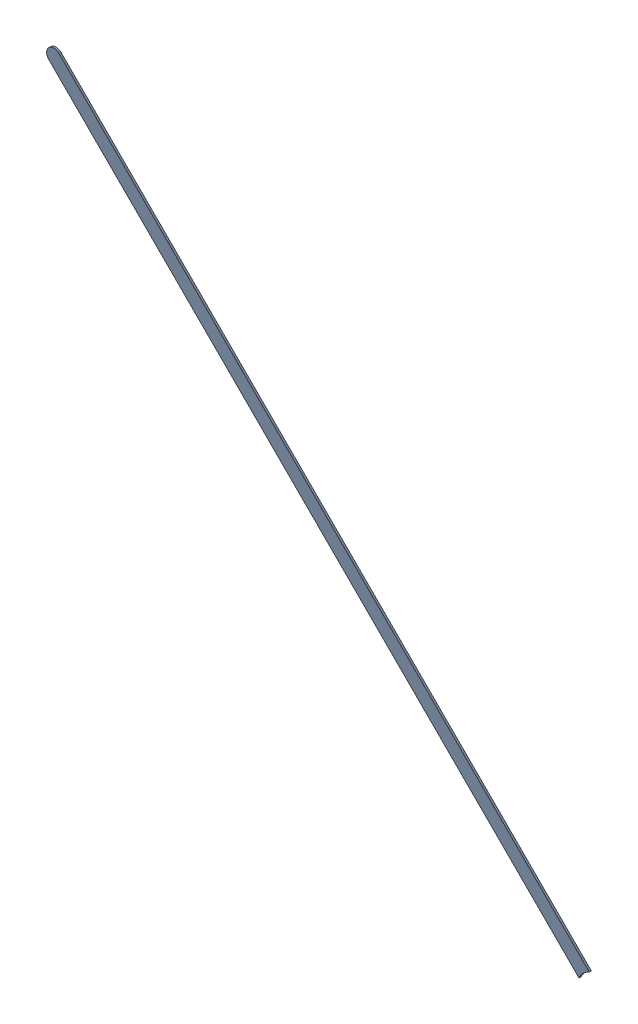
SolidWorks assembly Track (7.2mm,32mm)(16.7mm,22.5mm) on Bottom Layer, configuration Predeterminado. Lengths in mm.
Overall size (9.48 9.48 0.04).
2 component instances, 1 part files, 0 mates.
Components (placement in the parent):
- Track (7.2mm,32mm)(16.7mm,22.5mm) on Bottom Layer-1-1: Track (7.2mm,32mm)(16.7mm,22.5mm) on Bottom Layer-1 [Predeterminado] at (-68.317 -44.187 -0.4013) size (9.48 9.48 0.04)
  - Track (7.2mm,32mm)(16.7mm,22.5mm) on Bottom Layer-Part-1-1: Track (7.2mm,32mm)(16.7mm,22.5mm) on Bottom Layer-Part-1 [Predeterminado] at origin size (9.48 9.48 0.04)
